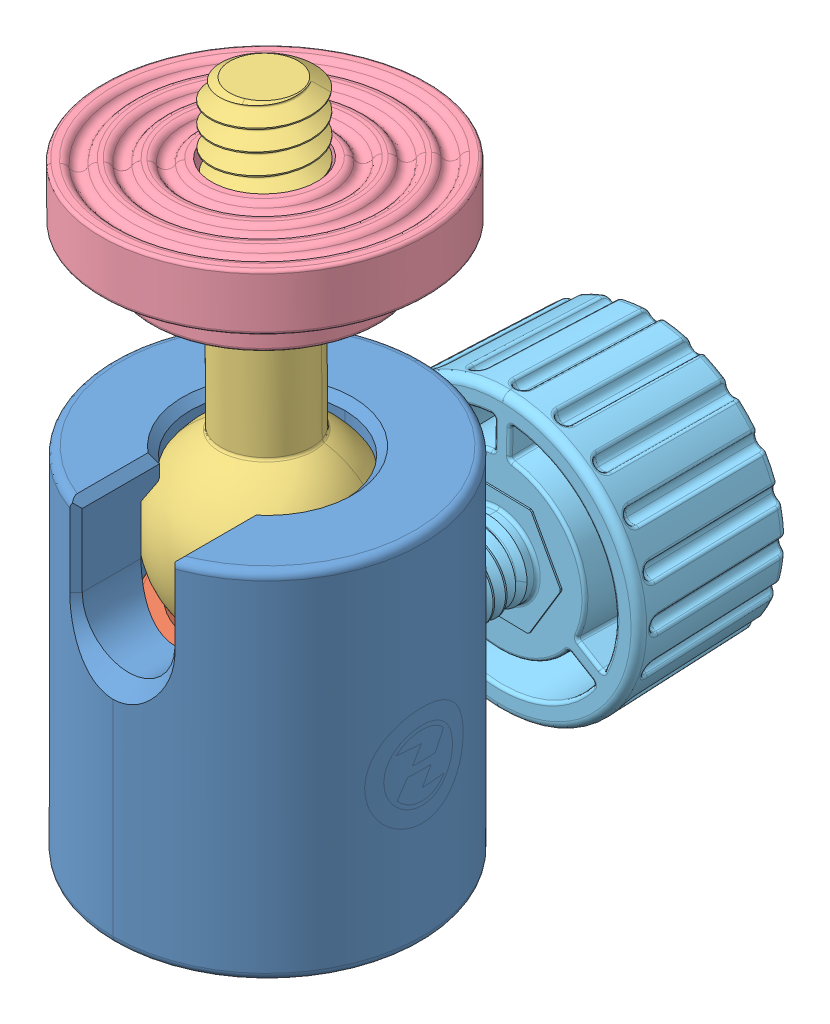
SolidWorks assembly Ball Head, configuration Default. Lengths in mm.
Overall size (42.71 44.87 45.01).
6 component instances, 5 part files, 0 mates.
Components (placement in the parent):
- Ball Head.IGS-1: Ball Head.IGS [Default] at origin size (42.71 44.87 45.01)
  - Gehäuse.IGS-1: Gehäuse.IGS [Default] at origin size (38.01 23.01 20.01)
  - Druckstück.IGS-1: Druckstück.IGS [Default] at (0 -0.5774 0) x (0.996351 0 0.085346) z (-0.085346 0 0.996351) size (23.21 15.61 12)
  - Kugelkopfschraube.IGS-1: Kugelkopfschraube.IGS [Default] at (0 18.5 0) x (0.937202 0.036262 -0.346898) z (0.344349 0.061981 0.936794) size (11.9 30.66 12.01)
  - Scheibe.IGS-1: Scheibe.IGS [Default] at (-0.7516 32.015 -0.6179) x (0.736904 0.071715 0.672182) z (-0.673717 -0.003682 0.73898) size (39.21 6.21 20)
  - Schraube.IGS-1: Schraube.IGS [Default] at (0 9.5 -14.9504) x (0 0 1) z (-0.999799 0.020029 0) size (21.11 18.19 33.94)
